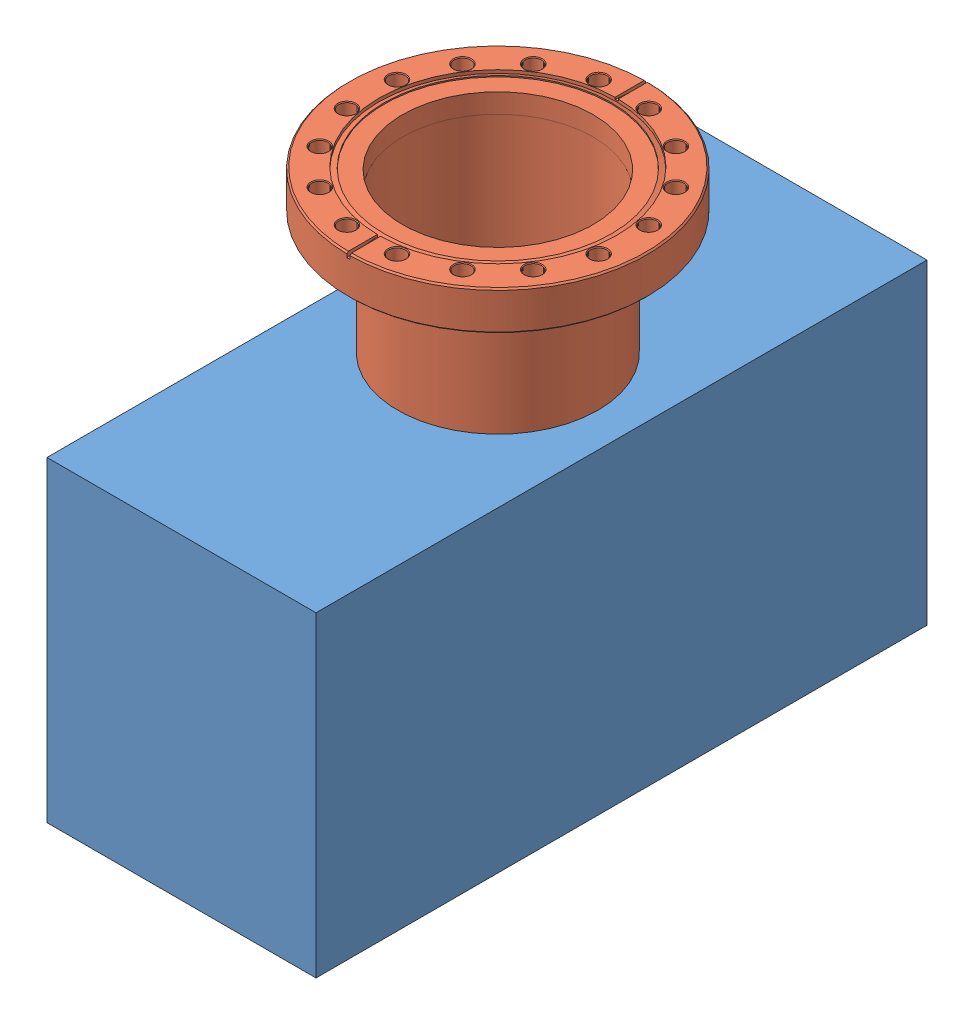
SolidWorks assembly vacion75pumpassembly_approx, configuration Default. Lengths in mm.
Overall size (151.64 242.09 310.01).
2 component instances, 2 part files, 3 mates.
Components (placement in the parent):
- vacion75pumpbody-1: vacion75pumpbody [Default] at (-78.4206 -100.7509 109.8301) size (136.5 160.48 310.01)
- 401006-1: 401006 [Default] at (-10.1708 121.5245 -50.6725) x (1 0 0) z (0 1 0) size (151.64 151.64 134.87)
Mates (geometry in assembly coordinates):
- Parallel1: parallel: plane of vacion75pumpbody-1 through (-78.4206 59.7263 -200.1769) normal (0 1 0); plane of 401006-1 through (-12.8577 141.3365 -74.7924) normal (0 1 0)
- Distance1: distance = 81.6102 mm: plane of 401006-1 through (-10.1708 141.3365 -50.6725) normal (0 1 0); plane of vacion75pumpbody-1 through (-78.4206 59.7263 -200.1769) normal (0 1 0)
- Concentric1: concentric anti-aligned: circle of vacion75pumpbody-1; circle of 401006-1
